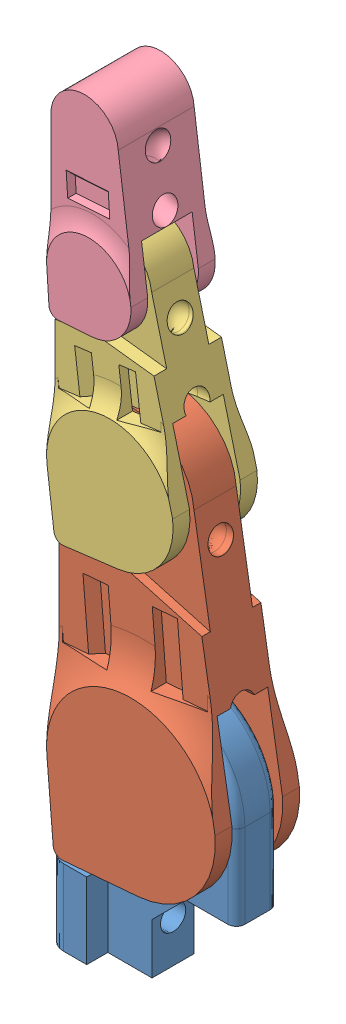
SolidWorks assembly rh1f3 v4, configuration Default. Lengths in mm.
4 component instances, 4 part files, 9 mates.
Components (placement in the parent):
- robot hand v4 f1 4-1: robot hand v4 f1 4 [Default] at (7.4493 16.7233 27.6774) x (0 1 0) z (0 0 1) size (30 20 10)
- rhf3l1-1: rhf3l1 [Default] at (6.1993 31.6711 27.6774) x (-0.083333 0.996522 0) z (0 0 1) size (47.5 21.81 12.12)
- rhf1l2-1: rhf1l2 [Default] at (3.6993 56.5405 27.6774) x (-0.125 0.992157 0) z (0 0 1) size (32.5 16.23 12)
- rhf1l3-1: rhf1l3 [Default] at (1.9493 73.9454 27.6774) x (-0.066667 0.997775 0) z (0 0 1) size (24 10.94 11)
Mates (geometry in assembly coordinates):
- Concentric1: concentric aligned: cylinder of robot hand v4 f1 4-1 through (7.4493 16.7233 30.1774) axis (0 0 -1) radius 3; cylinder of rhf3l1-1 through (7.4493 16.7233 32.6774) axis (0 0 -1) radius 2.5
- Concentric2: concentric aligned: cylinder of rhf3l1-1 through (4.9493 46.6189 32.1774) axis (0 0 -1) radius 3; cylinder of rhf1l2-1 through (4.9493 46.6189 32.6774) axis (0 0 -1) radius 2.5
- Concentric3: concentric aligned: cylinder of rhf1l2-1 through (2.4493 66.4621 32.1774) axis (0 0 -1) radius 3; cylinder of rhf1l3-1 through (2.4493 66.4621 32.6774) axis (0 0 -1) radius 2.5
- Width4: width: plane of robot hand v4 f1 4-1 through (7.4493 16.7233 30.1774) normal (0 0 1); plane of robot hand v4 f1 4-1 through (7.4493 16.7233 25.1774) normal (0 0 -1); plane of rhf3l1-1 through (6.1993 31.6711 30.6774) normal (0 0 -1); plane of rhf3l1-1 through (6.1993 31.6711 24.6774) normal (0 0 1)
- Width6: width: plane of rhf1l2-1 through (3.6993 56.5405 30.1774) normal (0 0 1); plane of rhf1l2-1 through (3.6993 56.5405 25.1774) normal (0 0 -1); plane of rhf1l3-1 through (1.9493 73.9454 24.6774) normal (0 0 1); plane of rhf1l3-1 through (1.9493 73.9454 30.6774) normal (0 0 -1)
- Coincident1: coincident aligned: plane of rhf1l2-1 through (-2.5507 56.5405 31.6774) normal (-1 0 0); plane of rhf3l1-1 through (-2.5507 31.6711 31.1774) normal (-1 0 0)
- Coincident2: coincident aligned: plane of robot hand v4 f1 4-1 through (-2.5507 16.7233 30.1774) normal (-1 0 0); plane of rhf3l1-1 through (-2.5507 31.6711 31.1774) normal (-1 0 0)
- Coincident3: coincident aligned: plane of rhf1l2-1 through (-2.5507 56.5405 31.6774) normal (-1 0 0); plane of rhf1l3-1 through (-2.5507 73.9454 29.6774) normal (-1 0 0)
- Width7: width: plane of rhf3l1-1 through (6.1993 31.6711 30.1774) normal (0 0 1); plane of rhf1l2-1 through (6.1993 31.6711 25.1774) normal (0 0 -1); plane of rhf3l1-1 through (3.6993 56.5405 30.6774) normal (0 0 -1); plane of rhf1l2-1 through (3.6993 56.5405 24.6774) normal (0 0 1)
